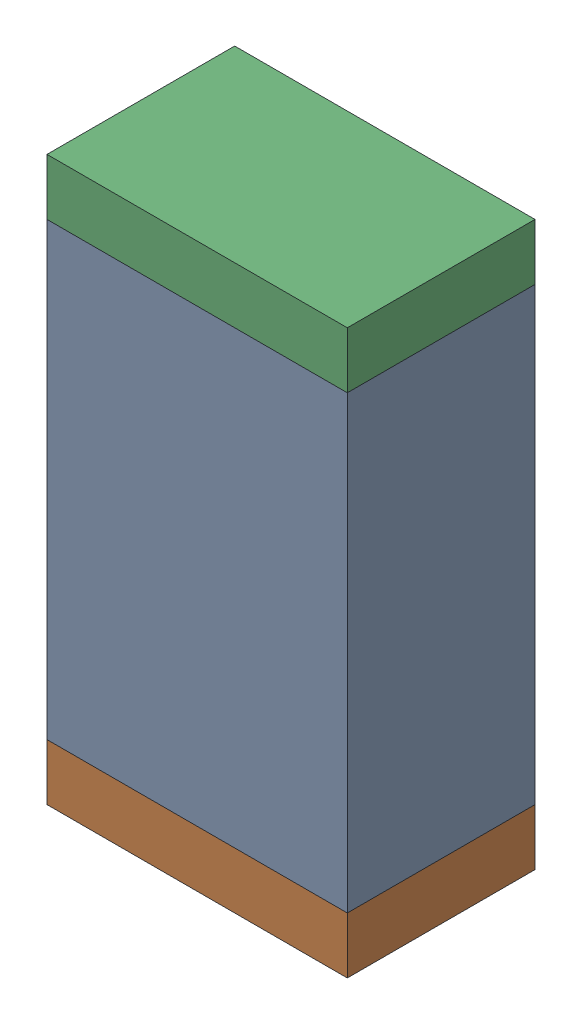
SolidWorks assembly R48, configuration Default. Lengths in mm.
Overall size (0.8 1.5 0.5).
6 component instances, 2 part files, 0 mates.
Components (placement in the parent):
- 810156976-1: 810156976 [Default] at (106.6 59.3 0) size (0.8 1.2 0.5)
  - Extruded_6-1: Extruded_6 [Default] at origin size (0.8 1.2 0.5)
- 810156592-1: 810156592 [Default] at (106.6 58.625 0) size (0.8 0.15 0.5)
  - Extruded_7-1: Extruded_7 [Default] at origin size (0.8 0.15 0.5)
- 810156592-2: 810156592 [Default] at (106.6 59.975 0) size (0.8 0.15 0.5)
  - Extruded_7-1: Extruded_7 [Default] at origin size (0.8 0.15 0.5)
